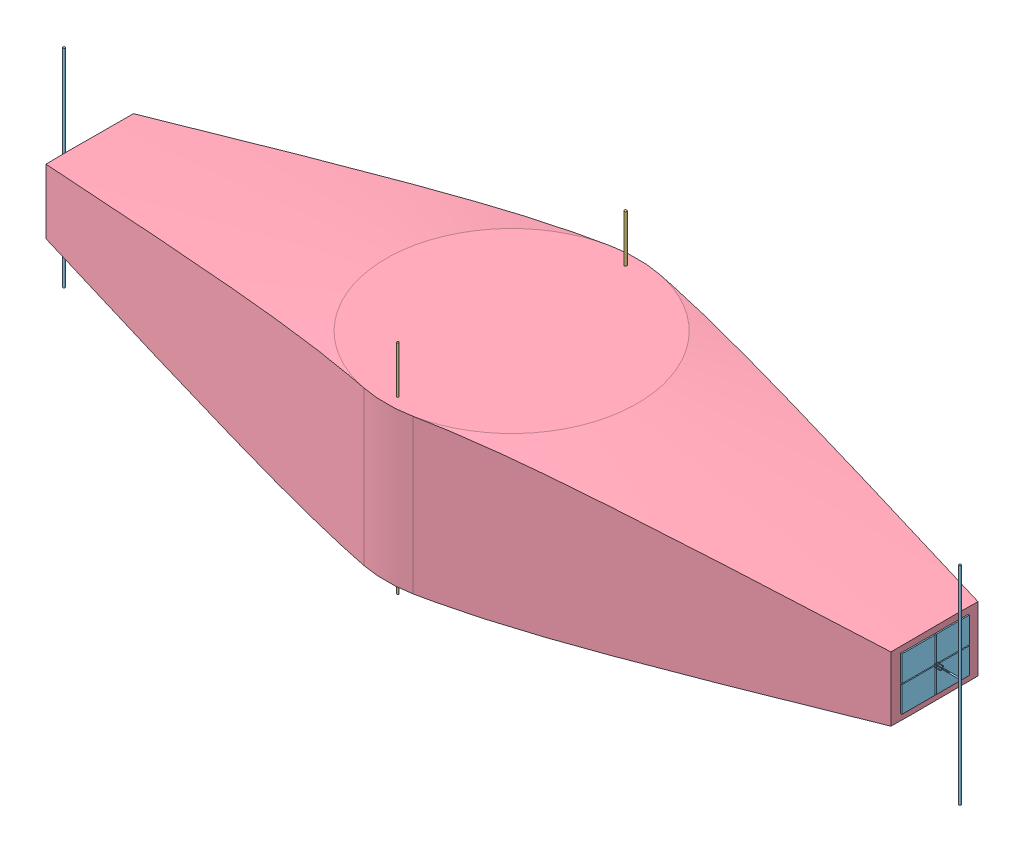
SolidWorks assembly Unit, configuration 默认. Lengths in mm.
Overall size (500 90.9 125.56).
6 component instances, 5 part files, 13 mates.
Components (placement in the parent):
- BEGeDet-1: BEGeDet [默认] at (2.9686 -23.0613 80) size (80 40 80)
- InnerShell-IV-1: InnerShell-IV [默认] at (2.9686 -23.1113 80) x (0.656103 0 0.754671) z (-0.754671 0 0.656103) size (89 50 89)
- Electronics-1: Electronics [默认] at (2.9686 -48.2113 80) x (-1 0 0) z (0 0 -1) size (21.21 85 89.7)
- OuterShell-IV-2: OuterShell-IV [默认] at (2.9686 -24.1113 80) size (500 60 98)
- SiPMArray-IV-1: SiPMArray-IV [默认] at (167.9686 -24.1113 80) size (10.4 81 26.4)
- SiPMArray-IV-2: SiPMArray-IV [默认] at (-161.6528 -24.1113 80) x (-1 0 0) z (0 0 -1) size (10.4 81 26.4)
Mates (geometry in assembly coordinates):
- 重合1: coincident anti-aligned: plane of BEGeDet-1 through (2.9686 -3.0613 80) normal (0 1 0); plane of InnerShell-IV-1 through (2.9686 -3.0613 80) normal (0 -1 0)
- 同心1: concentric aligned: circle of BEGeDet-1; circle of InnerShell-IV-1
- 同心14: concentric anti-aligned: circle of BEGeDet-1; circle of Electronics-1
- 重合10: coincident anti-aligned: plane of InnerShell-IV-1 through (2.9686 -48.1113 80) normal (0 -1 0); plane of Electronics-1 through (2.9686 -48.1113 60.201) normal (0 1 0)
- 重合11: coincident anti-aligned: circle of InnerShell-IV-1; plane of OuterShell-IV-2 through (2.9686 1.8887 80) normal (0 -1 0)
- 同心15: concentric aligned: circle of InnerShell-IV-1; circle of OuterShell-IV-2
- 平行1: parallel aligned: line of BEGeDet-1 through (2.9686 -43.0613 80) axis (1 0 0); line of OuterShell-IV-2 through (2.9686 -24.1113 80) axis (1 0 0)
- 垂直1: perpendicular: line of Electronics-1 through (3.1686 -48.2113 60.401) axis (0 0 -1); line of OuterShell-IV-2 through (2.9686 -24.1113 80) axis (1 0 0)
- 重合14: coincident anti-aligned: plane of OuterShell-IV-2 through (167.9686 -54.1121 63.0105) normal (1 0 0); plane of SiPMArray-IV-1 through (167.9686 -24.1113 80) normal (-1 0 0)
- 重合15: coincident: point of OuterShell-IV-2; point of SiPMArray-IV-1
- 重合18: coincident: plane of OuterShell-IV-2 through (-161.6528 -54.1121 97.0652) normal (-1 0 0); plane of SiPMArray-IV-2 through (-161.6528 -24.1113 80) normal (1 0 0)
- 重合19: coincident: point of OuterShell-IV-2; point of SiPMArray-IV-2
- 平行4: parallel anti-aligned: line of OuterShell-IV-2 through (-161.6528 -36.7228 62.9348) axis (0 1 0); line of SiPMArray-IV-2 through (-162.1528 -13.9113 66.8) axis (0 -1 0)
